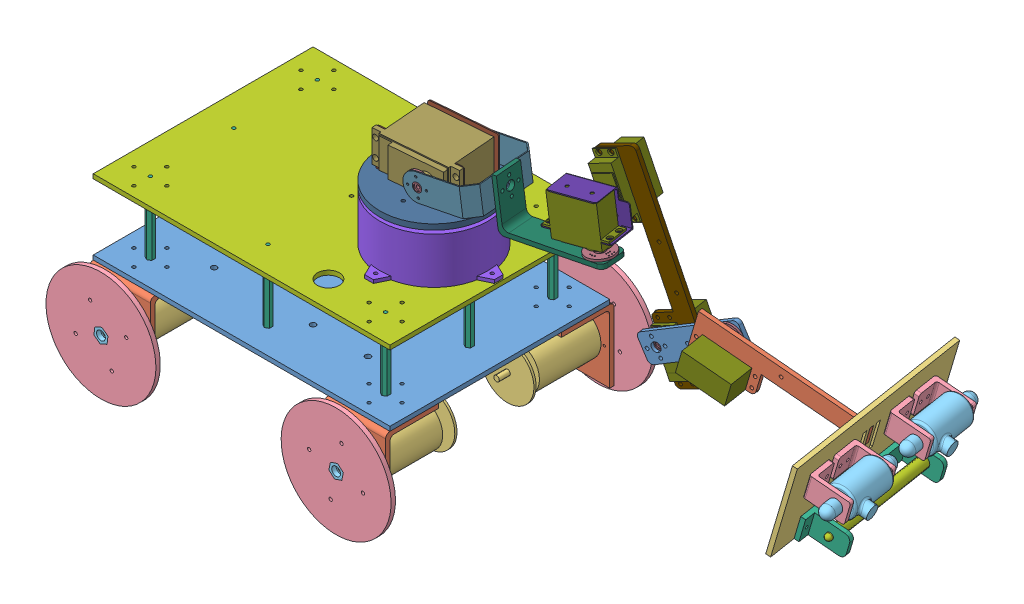
SolidWorks assembly robot, configuration Default. Lengths in mm.
Overall size (661.79 298.94 252.45).
55 component instances, 25 part files, 131 mates.
Components (placement in the parent):
- base_odroid_down_fix-1: base_odroid_down_fix [Default] at (39.4639 122.941 229.7749) x (1 0 0) z (0 -1 0) size (270 200 4)
- link_motor_1_port-1: link_motor_1_port [Default] at (221.3654 112.3394 287.3354) x (0 0 -1) z (1 0 0) size (48 66 56)
- motor_dc_NISCA-1: motor_dc_NISCA [Default] at (244.2642 39.7289 313.6416) x (0 -1 0) z (0 0 -1) size (54 48 92)
- roda_shaft-1: roda_shaft [Default] at (185.8398 121.6563 330.6416) x (-0.980223 0.197896 0) z (0 0 1) size (100 100 4)
- shaft_adapter_5mm-1: shaft_adapter_5mm [Default] at (248.7954 72.9583 317.6416) x (0.980223 -0.197896 0) z (0 0 1) size (12 13.86 17)
- link_motor_1_port-2: link_motor_1_port [Default] at (221.3654 112.3394 139.9479) x (0 0 1) z (-1 0 0) size (48 66 56)
- motor_dc_NISCA-2: motor_dc_NISCA [Default] at (198.4666 39.7289 113.6416) x (0 -1 0) z (0 0 1) size (54 48 92)
- shaft_adapter_5mm-3: shaft_adapter_5mm [Default] at (238.0112 59.5291 109.6416) x (0.404857 -0.91438 0) z (0 0 -1) size (12 13.86 17)
- roda_shaft-2: roda_shaft [Default] at (222.1063 135.748 96.6416) x (0.589448 0.807807 0) z (0 0 -1) size (100 100 4)
- link_motor_1_port-5: link_motor_1_port [Default] at (7.3654 112.3394 287.3354) x (0 0 -1) z (1 0 0) size (48 66 56)
- motor_dc_NISCA-5: motor_dc_NISCA [Default] at (-15.5334 128.1531 313.6416) x (0 1 0) z (0 0 -1) size (54 48 92)
- roda_shaft-5: roda_shaft [Default] at (51.5287 56.8466 334.6416) x (0.393495 -0.919327 0) z (0 0 -1) size (100 100 4)
- shaft_adapter_5mm-6: shaft_adapter_5mm [Default] at (0.8367 112.7577 317.6416) x (-0.393495 0.919327 0) z (0 0 1) size (12 13.86 17)
- link_motor_1_port-6: link_motor_1_port [Default] at (7.3654 112.3394 139.9479) x (0 0 1) z (-1 0 0) size (48 66 56)
- motor_dc_NISCA-6: motor_dc_NISCA [Default] at (-15.5334 39.7289 113.6416) x (0 -1 0) z (0 0 1) size (54 48 92)
- roda_shaft-6: roda_shaft [Default] at (45.258 48.6046 96.6416) x (0.202799 -0.97922 0) z (0 0 -1) size (100 100 4)
- shaft_adapter_5mm-7: shaft_adapter_5mm [Default] at (36.6325 79.8838 109.6416) x (0.949429 -0.313981 0) z (0 0 -1) size (12 13.86 17)
- spacer_6cm-2: spacer_6cm [Default] at (221.7099 182.941 288.7798) x (0.5 0 -0.866025) z (0 -1 0) size (6 6.93 68)
- spacer_6cm-3: spacer_6cm [Default] at (114.7099 182.941 288.7798) x (0.5 0 -0.866025) z (0 -1 0) size (6 6.93 68)
- spacer_6cm-4: spacer_6cm [Default] at (7.7099 182.941 288.7798) x (0.5 0 -0.866025) z (0 -1 0) size (6 6.93 68)
- spacer_6cm-5: spacer_6cm [Default] at (221.7099 182.941 212.7798) x (0.5 0 -0.866025) z (0 -1 0) size (6 6.93 68)
- spacer_6cm-7: spacer_6cm [Default] at (7.7099 182.941 212.7798) x (0.5 0 -0.866025) z (0 -1 0) size (6 6.93 68)
- spacer_6cm-8: spacer_6cm [Default] at (221.7099 182.941 136.7798) x (0.5 0 -0.866025) z (0 -1 0) size (6 6.93 68)
- spacer_6cm-9: spacer_6cm [Default] at (114.7099 182.941 136.7798) x (0.5 0 -0.866025) z (0 -1 0) size (6 6.93 68)
- spacer_6cm-10: spacer_6cm [Default] at (7.7099 182.941 136.7798) x (0.5 0 -0.866025) z (0 -1 0) size (6 6.93 68)
- base_odroid_up_fix-1: base_odroid_up_fix [Default] at (189.2669 186.941 197.5083) x (-1 0 0) z (0 -1 0) size (270 200 4)
- base_arm-1: base_arm [Default] at (189.3654 194.0898 219.4289) x (0 0 1) z (-1 0 0) size (118.01 42 118.01)
- servo_hs422-1: servo_hs422 [Default] at (199.6524 210.6756 203.7356) x (0 0 1) z (-1 0 0) size (19.81 42.14 58.23)
- link1_arm-1: link1_arm [Default] at (162.8005 232.0663 215.7774) x (-0.996784 0 0.080141) z (0 1 0) size (98 98 12)
- bracket_servo_hs755-1: bracket_servo_hs755 [Default] at (229.3889 266.4802 249.7627) x (0.080141 0 0.996784) z (-0.996784 0 0.080141) size (44 34 74)
- servo_hs755-1: servo_hs755 [Default] at (197.4303 211.9363 187.9125) x (0 -1 0) z (0.080141 0 0.996784) size (29 74 56.99)
- servo_horn_general-1: servo_horn_general [Default] at (161.8295 247.7173 249.9552) x (-0.987951 -0.132827 0.07943) z (-0.080141 0 -0.996784) size (24 24 6)
- link2_ubracket-2: link2_ubracket [Default] at (240.8328 274.1378 198.1638) x (-0.080141 0 -0.996784) z (0.1324 -0.991139 -0.010645) size (66 59 24)
- link2_fix-2: link2_fix [Default] at (299.0179 277.8626 194.3678) x (-0.1324 0.991139 0.010645) z (0.080141 0 0.996784) size (45.14 89 24)
- servo_horn_general-2: servo_horn_general [Default] at (284.7702 239.5829 204.3668) x (-0.987951 -0.132827 0.07943) z (-0.1324 0.991139 0.010645) size (24 24 6)
- servo_hs645-2: servo_hs645 [Default] at (369.3996 295.5758 210.2508) x (0.977362 0.132332 -0.165079) z (0.1324 -0.991139 -0.010645) size (53.34 19.56 42.35)
- bracket_servo_645-2: bracket_servo_645 [Default] at (347.8726 246.1813 195.0971) x (0.1324 -0.991139 -0.010645) z (-0.977362 -0.132332 0.165079) size (34 24 57)
- servo_horn_general-3: servo_horn_general [Default] at (277.6371 270.7769 198.3256) x (-0.978327 0.128702 0.162209) z (-0.165025 -0.011453 -0.986223) size (24 24 6)
- servo_hs645-3: servo_hs645 [Default] at (344.7059 232.8318 142.5694) x (0.379271 -0.923782 -0.052736) z (0.165025 0.011453 0.986223) size (53.34 19.56 42.35)
- link4_fix-1: link4_fix [Default] at (380.9777 101.6658 161.2675) x (0.379271 -0.923782 -0.052736) z (0.165025 0.011453 0.986223) size (176.25 35 4)
- servo_hs645-4: servo_hs645 [Default] at (325.2729 210.3912 140.3518) x (-0.379271 0.923782 0.052736) z (0.165025 0.011453 0.986223) size (53.34 19.56 42.35)
- link5_fix-1: link5_fix [Default] at (359.9362 227.0912 179.3318) x (-0.462668 0.883985 0.067153) z (0.165025 0.011453 0.986223) size (24 90 4)
- servo_horn_general-4: servo_horn_general [Default] at (321.7006 151.6934 186.6053) x (-0.871037 -0.467376 0.151178) z (-0.165025 -0.011453 -0.986223) size (24 24 6)
- servo_horn_general-5: servo_horn_general [Default] at (461.1917 226.2323 166.4545) x (0.871037 0.467376 -0.151178) z (0.165025 0.011453 0.986223) size (24 24 6)
- servo_hs645-5: servo_hs645 [Default] at (388.7583 231.4902 223.4879) x (-0.953883 0.25607 0.15664) z (-0.165025 -0.011453 -0.986223) size (53.34 19.56 42.35)
- link6_eff-1: link6_eff [Default] at (386.3105 210.0758 200.9019) x (-0.953883 0.25607 0.15664) z (-0.165025 -0.011453 -0.986223) size (140.63 35 4)
- base_link_effector_fix-2: base_link_effector_fix [Default] at (543.3424 202.5775 175.4232) x (-0.165025 -0.011453 -0.986223) z (0.953883 -0.25607 -0.15664) size (180 80 4)
- base_webcam_fix1-2: base_webcam_fix1 [Default] at (558.36 202.6941 241.1484) x (-0.165025 -0.011453 -0.986223) z (-0.250748 -0.96659 0.053182) size (23 34 20)
- base_webcam_fix1-3: base_webcam_fix1 [Default] at (544.9288 182.7782 191.9147) x (0.165025 0.011453 0.986223) z (0.250748 0.96659 -0.053182) size (23 34 20)
- base_webcam_fix1-4: base_webcam_fix1 [Default] at (543.6728 201.6748 153.3746) x (-0.165025 -0.011453 -0.986223) z (-0.250748 -0.96659 0.053182) size (23 34 20)
- base_webcam_fix1-5: base_webcam_fix1 [Default] at (530.2416 181.7589 104.1409) x (0.165025 0.011453 0.986223) z (0.250748 0.96659 -0.053182) size (23 34 20)
- webcam_sturdy-3: webcam_sturdy [Default] at (570.2782 186.2948 187.3169) x (-0.165025 -0.011453 -0.986223) z (0.953883 -0.25607 -0.15664) size (79 27 33.5)
- webcam_sturdy-4: webcam_sturdy [Default] at (555.5909 185.2756 99.5431) x (-0.165025 -0.011453 -0.986223) z (0.953883 -0.25607 -0.15664) size (79 27 33.5)
- base_GM-1: base_GM [Default] at (537.7124 159.212 133.8436) x (-0.165025 -0.011453 -0.986223) z (-0.250748 -0.96659 0.053182) size (128 34 20)
- tabung_GM-1: tabung_GM [Default] at (565.3856 190.6554 118.4363) x (0.246294 0.967775 -0.052451) z (0.165025 0.011453 0.986223) size (10 10 116)
Mates (geometry in assembly coordinates):
- Coincident1: coincident anti-aligned: plane of link_motor_1_port-1 through (193.3654 52.941 313.6416) normal (0 0 -1); plane of motor_dc_NISCA-1 through (221.3654 83.941 313.6416) normal (0 0 1)
- Concentric1: concentric aligned: cylinder of link_motor_1_port-1 through (221.3654 83.941 317.6416) axis (0 0 -1) radius 9.5; cylinder of motor_dc_NISCA-1 through (221.3654 83.941 317.6416) axis (0 0 -1) radius 9
- Concentric2: concentric anti-aligned: cylinder of link_motor_1_port-1 through (221.3654 106.941 317.6416) axis (0 0 -1) radius 1; cylinder of motor_dc_NISCA-1 through (221.3654 106.941 311.6416) axis (0 0 1) radius 1.5
- Coincident2: coincident anti-aligned: plane of motor_dc_NISCA-1 through (244.2642 39.7289 317.6416) normal (0 0 1); plane of shaft_adapter_5mm-1 through (221.3654 83.941 317.6416) normal (0 0 -1)
- Concentric4: concentric aligned: cylinder of motor_dc_NISCA-1 through (221.3654 83.941 330.6416) axis (0 0 -1) radius 2.5; cylinder of shaft_adapter_5mm-1 through (221.3654 83.941 330.6416) axis (0 0 -1) radius 2.5
- Coincident3: coincident anti-aligned: plane of roda_shaft-1 through (222.7365 90.7322 330.6416) normal (0.318728 -0.947846 0); plane of shaft_adapter_5mm-1 through (222.7365 90.7322 334.6416) normal (-0.318728 0.947846 0)
- Coincident4: coincident aligned: plane of roda_shaft-1 through (221.3654 83.941 334.6416) normal (0 0 1); plane of shaft_adapter_5mm-1 through (248.7954 72.9583 334.6416) normal (0 0 1)
- Coincident7: coincident anti-aligned: plane of roda_shaft-1 through (214.7985 81.7328 330.6416) normal (0.661495 0.74995 0); plane of shaft_adapter_5mm-1 through (214.7985 81.7328 334.6416) normal (-0.661495 -0.74995 0)
- Coincident8: coincident anti-aligned: plane of link_motor_1_port-2 through (249.3654 52.941 113.6416) normal (0 0 1); plane of motor_dc_NISCA-2 through (221.3654 83.941 113.6416) normal (0 0 -1)
- Concentric5: concentric aligned: cylinder of link_motor_1_port-2 through (221.3654 83.941 109.6416) axis (0 0 1) radius 9.5; cylinder of motor_dc_NISCA-2 through (221.3654 83.941 109.6416) axis (0 0 1) radius 9
- Concentric7: concentric anti-aligned: cylinder of link_motor_1_port-2 through (221.3654 106.941 109.6416) axis (0 0 1) radius 1; cylinder of motor_dc_NISCA-2 through (221.3654 106.941 115.6416) axis (0 0 -1) radius 1.5
- Coincident9: coincident anti-aligned: plane of base_odroid_down_fix-1 through (39.4639 118.941 229.7749) normal (0 -1 0); plane of link_motor_1_port-1 through (193.3654 118.941 269.6416) normal (0 1 0)
- Concentric8: concentric anti-aligned: cylinder of base_odroid_down_fix-1 through (206.3654 118.941 289.6416) axis (0 1 0) radius 1.5; cylinder of link_motor_1_port-1 through (206.3654 118.941 289.6416) axis (0 -1 0) radius 1.5
- Concentric9: concentric anti-aligned: cylinder of base_odroid_down_fix-1 through (236.3654 118.941 289.6416) axis (0 1 0) radius 1.5; cylinder of link_motor_1_port-1 through (236.3654 118.941 289.6416) axis (0 -1 0) radius 1.5
- Coincident11: coincident aligned: plane of shaft_adapter_5mm-3 through (238.0112 59.5291 92.6416) normal (0 0 -1); plane of roda_shaft-2 through (221.3654 83.941 92.6416) normal (0 0 -1)
- Coincident12: coincident anti-aligned: plane of shaft_adapter_5mm-3 through (220.627 77.0523 92.6416) normal (-0.589448 -0.807807 0); plane of roda_shaft-2 through (220.627 77.0523 96.6416) normal (0.589448 0.807807 0)
- Coincident13: coincident anti-aligned: plane of shaft_adapter_5mm-3 through (227.7004 86.746 92.6416) normal (0.994305 -0.106573 0); plane of roda_shaft-2 through (227.7004 86.746 96.6416) normal (-0.994305 0.106573 0)
- Coincident14: coincident anti-aligned: plane of motor_dc_NISCA-2 through (198.4666 39.7289 109.6416) normal (0 0 -1); plane of shaft_adapter_5mm-3 through (221.3654 83.941 109.6416) normal (0 0 1)
- Concentric10: concentric aligned: cylinder of motor_dc_NISCA-2 through (221.3654 83.941 96.6416) axis (0 0 1) radius 2.5; cylinder of shaft_adapter_5mm-3 through (221.3654 83.941 96.6416) axis (0 0 1) radius 2.5
- Coincident15: coincident anti-aligned: plane of base_odroid_down_fix-1 through (39.4639 118.941 229.7749) normal (0 -1 0); plane of link_motor_1_port-2 through (249.3654 118.941 157.6416) normal (0 1 0)
- Concentric11: concentric anti-aligned: cylinder of base_odroid_down_fix-1 through (206.3654 118.941 137.6416) axis (0 1 0) radius 1.5; cylinder of link_motor_1_port-2 through (206.3654 118.941 137.6416) axis (0 -1 0) radius 1.5
- Concentric12: concentric anti-aligned: cylinder of base_odroid_down_fix-1 through (236.3654 118.941 137.6416) axis (0 1 0) radius 1.5; cylinder of link_motor_1_port-2 through (236.3654 118.941 137.6416) axis (0 -1 0) radius 1.5
- Coincident16: coincident anti-aligned: plane of link_motor_1_port-5 through (-20.6346 52.941 313.6416) normal (0 0 -1); plane of motor_dc_NISCA-5 through (7.3654 83.941 313.6416) normal (0 0 1)
- Concentric13: concentric aligned: cylinder of link_motor_1_port-5 through (7.3654 83.941 317.6416) axis (0 0 -1) radius 9.5; cylinder of motor_dc_NISCA-5 through (7.3654 83.941 317.6416) axis (0 0 -1) radius 9
- Concentric14: concentric anti-aligned: cylinder of link_motor_1_port-5 through (7.3654 106.941 317.6416) axis (0 0 -1) radius 1; cylinder of motor_dc_NISCA-5 through (7.3654 106.941 311.6416) axis (0 0 1) radius 1.5
- Concentric16: concentric aligned: cylinder of motor_dc_NISCA-5 through (7.3654 83.941 330.6416) axis (0 0 -1) radius 2.5; cylinder of shaft_adapter_5mm-6 through (7.3654 83.941 330.6416) axis (0 0 -1) radius 2.5
- Coincident17: coincident anti-aligned: plane of motor_dc_NISCA-5 through (-15.5334 128.1531 317.6416) normal (0 0 1); plane of shaft_adapter_5mm-6 through (7.3654 83.941 317.6416) normal (0 0 -1)
- Coincident18: coincident anti-aligned: plane of roda_shaft-5 through (6.5417 77.062 334.6416) normal (0.599413 0.80044 0); plane of shaft_adapter_5mm-6 through (0.9961 81.2148 334.6416) normal (-0.599413 -0.80044 0)
- Coincident19: coincident aligned: plane of roda_shaft-5 through (7.3654 83.941 334.6416) normal (0 0 1); plane of shaft_adapter_5mm-6 through (0.8367 112.7577 334.6416) normal (0 0 1)
- Coincident20: coincident anti-aligned: plane of roda_shaft-5 through (1.8198 88.0939 334.6416) normal (0.393495 -0.919327 0); plane of shaft_adapter_5mm-6 through (8.1891 90.8201 334.6416) normal (-0.393495 0.919327 0)
- Coincident21: coincident anti-aligned: plane of base_odroid_down_fix-1 through (39.4639 118.941 229.7749) normal (0 -1 0); plane of link_motor_1_port-5 through (-20.6346 118.941 269.6416) normal (0 1 0)
- Concentric17: concentric anti-aligned: cylinder of base_odroid_down_fix-1 through (-7.6346 118.941 289.6416) axis (0 1 0) radius 1.5; cylinder of link_motor_1_port-5 through (-7.6346 118.941 289.6416) axis (0 -1 0) radius 1.5
- Concentric18: concentric anti-aligned: cylinder of base_odroid_down_fix-1 through (22.3654 118.941 289.6416) axis (0 1 0) radius 1.5; cylinder of link_motor_1_port-5 through (22.3654 118.941 289.6416) axis (0 -1 0) radius 1.5
- Coincident22: coincident anti-aligned: plane of link_motor_1_port-6 through (35.3654 52.941 113.6416) normal (0 0 1); plane of motor_dc_NISCA-6 through (7.3654 83.941 113.6416) normal (0 0 -1)
- Concentric19: concentric aligned: cylinder of link_motor_1_port-6 through (7.3654 83.941 109.6416) axis (0 0 1) radius 9.5; cylinder of motor_dc_NISCA-6 through (7.3654 83.941 109.6416) axis (0 0 1) radius 9
- Concentric20: concentric anti-aligned: cylinder of link_motor_1_port-6 through (7.3654 106.941 109.6416) axis (0 0 1) radius 1; cylinder of motor_dc_NISCA-6 through (7.3654 106.941 115.6416) axis (0 0 -1) radius 1.5
- Concentric21: concentric aligned: cylinder of motor_dc_NISCA-6 through (7.3654 83.941 96.6416) axis (0 0 1) radius 2.5; cylinder of shaft_adapter_5mm-7 through (7.3654 83.941 96.6416) axis (0 0 1) radius 2.5
- Coincident23: coincident anti-aligned: plane of motor_dc_NISCA-6 through (-15.5334 39.7289 109.6416) normal (0 0 -1); plane of shaft_adapter_5mm-7 through (7.3654 83.941 109.6416) normal (0 0 1)
- Coincident24: coincident aligned: plane of roda_shaft-6 through (7.3654 83.941 92.6416) normal (0 0 -1); plane of shaft_adapter_5mm-7 through (36.6325 79.8838 92.6416) normal (0 0 -1)
- Coincident25: coincident anti-aligned: plane of roda_shaft-6 through (2.7565 89.1138 96.6416) normal (0.202799 -0.97922 0); plane of shaft_adapter_5mm-7 through (2.7565 89.1138 92.6416) normal (-0.202799 0.97922 0)
- Coincident26: coincident anti-aligned: plane of roda_shaft-6 through (5.1901 77.3632 96.6416) normal (0.74663 0.665239 0); plane of shaft_adapter_5mm-7 through (5.1901 77.3632 92.6416) normal (-0.74663 -0.665239 0)
- Coincident27: coincident anti-aligned: plane of base_odroid_down_fix-1 through (39.4639 118.941 229.7749) normal (0 -1 0); plane of link_motor_1_port-6 through (35.3654 118.941 157.6416) normal (0 1 0)
- Concentric22: concentric anti-aligned: cylinder of base_odroid_down_fix-1 through (-7.6346 118.941 137.6416) axis (0 1 0) radius 1.5; cylinder of link_motor_1_port-6 through (-7.6346 118.941 137.6416) axis (0 -1 0) radius 1.5
- Concentric23: concentric anti-aligned: cylinder of base_odroid_down_fix-1 through (22.3654 118.941 137.6416) axis (0 1 0) radius 1.5; cylinder of link_motor_1_port-6 through (22.3654 118.941 137.6416) axis (0 -1 0) radius 1.5
- Concentric24: concentric aligned: cylinder of base_odroid_down_fix-1 through (221.3654 118.941 289.6416) axis (0 1 0) radius 1.5; cylinder of spacer_6cm-2 through (221.3654 118.941 289.6416) axis (0 1 0) radius 1.5
- Coincident28: coincident anti-aligned: plane of base_odroid_down_fix-1 through (39.4639 122.941 229.7749) normal (0 1 0); plane of spacer_6cm-2 through (221.7099 122.941 288.7798) normal (0 -1 0)
- Parallel2: parallel aligned: plane of base_odroid_down_fix-1 through (249.3654 118.941 229.7749) normal (1 0 0); plane of spacer_6cm-2 through (224.3654 122.941 287.9096) normal (1 0 0)
- Concentric25: concentric anti-aligned: cylinder of spacer_6cm-2 through (221.3654 186.941 289.6416) axis (0 -1 0) radius 1.5; cylinder of base_odroid_up_fix-1 through (221.3654 182.941 289.6416) axis (0 1 0) radius 1.5
- Concentric26: concentric anti-aligned: cylinder of spacer_6cm-7 through (7.3654 186.941 213.6416) axis (0 -1 0) radius 1.5; cylinder of base_odroid_up_fix-1 through (7.3654 182.941 213.6416) axis (0 1 0) radius 1.5
- Coincident29: coincident anti-aligned: plane of spacer_6cm-2 through (221.7099 182.941 288.7798) normal (0 1 0); plane of base_odroid_up_fix-1 through (189.2669 182.941 197.5083) normal (0 -1 0)
- Coincident31: coincident anti-aligned: plane of base_arm-1 through (189.3654 225.941 213.6416) normal (0 -1 0); plane of servo_hs422-1 through (199.6524 225.941 203.7356) normal (0 1 0)
- Parallel3: parallel aligned: plane of base_odroid_up_fix-1 through (249.3654 182.941 197.5083) normal (1 0 0); plane of servo_hs422-1 through (219.5914 210.6756 223.5476) normal (1 0 0)
- Coincident33: coincident anti-aligned: plane of base_odroid_up_fix-1 through (189.2669 186.941 197.5083) normal (0 1 0); plane of base_arm-1 through (189.3654 186.941 259.6416) normal (0 -1 0)
- Concentric28: concentric anti-aligned: cylinder of base_odroid_up_fix-1 through (242.3654 182.941 213.6416) axis (0 1 0) radius 1.5; cylinder of base_arm-1 through (242.3654 189.941 213.6416) axis (0 -1 0) radius 1.5
- Concentric29: concentric anti-aligned: cylinder of base_odroid_up_fix-1 through (189.3654 182.941 160.6416) axis (0 1 0) radius 1.5; cylinder of base_arm-1 through (189.3654 189.941 160.6416) axis (0 -1 0) radius 1.5
- Parallel5: parallel aligned: plane of base_odroid_up_fix-1 through (189.2669 182.941 113.6416) normal (0 0 -1); plane of servo_hs422-1 through (199.6524 210.6756 203.7356) normal (0 0 -1)
- Concentric30: concentric aligned: cylinder of base_arm-1 through (189.3654 225.941 213.6416) axis (0 1 0) radius 5.4623; cylinder of servo_hs422-1 through (189.3654 202.0734 213.6416) axis (0 1 0) radius 6.4897
- Concentric31: concentric aligned: cylinder of servo_hs422-1 through (189.3654 212.8107 213.6416) axis (0 1 0) radius 2.8131; cylinder of link1_arm-1 through (189.3654 228.0663 213.6416) axis (0 1 0) radius 3
- Coincident36: coincident anti-aligned: plane of servo_hs422-1 through (199.6524 232.0663 223.5476) normal (0 1 0); plane of link1_arm-1 through (189.3654 232.0663 213.6416) normal (0 -1 0)
- Concentric32: concentric aligned: cylinder of link1_arm-1 through (189.3654 240.0663 213.6416) axis (0 -1 0) radius 4; cylinder of bracket_servo_hs755-1 through (189.3654 238.0663 213.6416) axis (0 -1 0) radius 4
- Coincident38: coincident anti-aligned: plane of link1_arm-1 through (189.3654 237.0663 213.6416) normal (0 1 0); plane of bracket_servo_hs755-1 through (150.0802 237.0663 186.7033) normal (0 -1 0)
- Concentric33: concentric anti-aligned: cylinder of link1_arm-1 through (181.3911 232.0663 214.2827) axis (0 1 0) radius 1.5; cylinder of bracket_servo_hs755-1 through (181.3911 238.0663 214.2827) axis (0 -1 0) radius 1.5
- Coincident40: coincident anti-aligned: plane of bracket_servo_hs755-1 through (153.6064 237.0663 230.5618) normal (0.080141 0 0.996784); plane of servo_hs755-1 through (200.5558 211.9363 226.7871) normal (-0.080141 0 -0.996784)
- Concentric36: concentric aligned: cylinder of bracket_servo_hs755-1 through (156.5166 248.5663 229.3246) axis (0.080141 0 0.996784) radius 1.5; cylinder of servo_hs755-1 through (156.5967 248.5663 230.3214) axis (0.080141 0 0.996784) radius 2.5
- Concentric37: concentric aligned: cylinder of bracket_servo_hs755-1 through (224.2979 264.5663 223.875) axis (0.080141 0 0.996784) radius 1.5; cylinder of servo_hs755-1 through (224.378 264.5663 224.8718) axis (0.080141 0 0.996784) radius 2.5
- Concentric39: concentric anti-aligned: cylinder of servo_hs755-1 through (207.3792 257.0663 244.2865) axis (-0.080141 0 -0.996784) radius 3; cylinder of servo_horn_general-1 through (207.1388 257.0663 241.2962) axis (0.080141 0 0.996784) radius 3
- Coincident41: coincident anti-aligned: plane of servo_hs755-1 through (207.3792 257.0663 244.2865) normal (0.080141 0 0.996784); plane of servo_horn_general-1 through (207.3792 257.0663 244.2865) normal (-0.080141 0 -0.996784)
- Concentric40: concentric anti-aligned: cylinder of servo_horn_general-1 through (207.6197 257.0663 247.2769) axis (-0.080141 0 -0.996784) radius 4; cylinder of link2_ubracket-2 through (207.5395 257.0663 246.2801) axis (0.080141 0 0.996784) radius 4
- Coincident42: coincident anti-aligned: plane of servo_horn_general-1 through (207.5395 257.0663 246.2801) normal (0.080141 0 0.996784); plane of link2_ubracket-2 through (245.852 250.11 243.1998) normal (-0.080141 0 -0.996784)
- Concentric41: concentric aligned: cylinder of servo_horn_general-1 through (206.32 264.9954 244.3717) axis (0.080141 0 0.996784) radius 0.5; cylinder of link2_ubracket-2 through (206.4803 264.9954 246.3653) axis (0.080141 0 0.996784) radius 1
- Coincident46: coincident anti-aligned: plane of link2_ubracket-2 through (254.8877 251.4155 234.032) normal (0.987951 0.132827 -0.07943); plane of link2_fix-2 through (251.2849 271.1865 222.2829) normal (-0.987951 -0.132827 0.07943)
- Concentric45: concentric anti-aligned: cylinder of link2_ubracket-2 through (250.3876 263.1763 210.3164) axis (0.987951 0.132827 -0.07943) radius 4; cylinder of link2_fix-2 through (255.3273 263.8405 209.9192) axis (-0.987951 -0.132827 0.07943) radius 4
- Concentric46: concentric anti-aligned: cylinder of link2_ubracket-2 through (249.7465 263.1763 202.3421) axis (0.987951 0.132827 -0.07943) radius 1; cylinder of link2_fix-2 through (254.6862 263.8405 201.9449) axis (-0.987951 -0.132827 0.07943) radius 1.5
- Coincident47: coincident anti-aligned: plane of servo_horn_general-2 through (330.8902 247.7672 203.844) normal (-0.1324 0.991139 0.010645); plane of servo_hs645-2 through (330.8902 247.7672 203.844) normal (0.1324 -0.991139 -0.010645)
- Concentric48: concentric anti-aligned: cylinder of servo_horn_general-2 through (330.493 250.7406 203.8759) axis (0.1324 -0.991139 -0.010645) radius 3; cylinder of servo_hs645-2 through (330.8902 247.7672 203.844) axis (-0.1324 0.991139 0.010645) radius 2.9972
- Coincident48: coincident anti-aligned: plane of link2_fix-2 through (305.7008 242.2334 217.9079) normal (-0.1324 0.991139 0.010645); plane of servo_horn_general-2 through (331.155 245.785 203.8227) normal (0.1324 -0.991139 -0.010645)
- Concentric49: concentric anti-aligned: cylinder of link2_fix-2 through (331.155 245.785 203.8227) axis (0.1324 -0.991139 -0.010645) radius 4; cylinder of servo_horn_general-2 through (331.2874 244.7938 203.8121) axis (-0.1324 0.991139 0.010645) radius 4
- Concentric50: concentric aligned: cylinder of link2_fix-2 through (330.5138 245.785 195.8485) axis (0.1324 -0.991139 -0.010645) radius 1.5; cylinder of servo_horn_general-2 through (330.249 247.7672 195.8697) axis (0.1324 -0.991139 -0.010645) radius 0.5
- Coincident50: coincident anti-aligned: plane of servo_hs645-2 through (373.1829 267.254 209.9466) normal (0.1324 -0.991139 -0.010645); plane of bracket_servo_645-2 through (288.6446 256.0929 197.6682) normal (-0.1324 0.991139 0.010645)
- Concentric51: concentric aligned: cylinder of servo_hs645-2 through (342.6829 266.414 207.0627) axis (0.1324 -0.991139 -0.010645) radius 2.5019; cylinder of bracket_servo_645-2 through (342.8994 264.7935 207.0453) axis (0.1324 -0.991139 -0.010645) radius 1.5
- Concentric52: concentric aligned: cylinder of servo_hs645-2 through (295.5154 260.0277 215.0294) axis (0.1324 -0.991139 -0.010645) radius 2.5019; cylinder of bracket_servo_645-2 through (295.7319 258.4072 215.012) axis (0.1324 -0.991139 -0.010645) radius 1.5
- Concentric53: concentric aligned: cylinder of bracket_servo_645-2 through (323.8802 267.9272 191.6347) axis (-0.165025 -0.011453 -0.986223) radius 4; cylinder of servo_horn_general-3 through (323.8802 267.9272 191.6347) axis (-0.165025 -0.011453 -0.986223) radius 4
- Coincident51: coincident anti-aligned: plane of bracket_servo_645-2 through (284.6399 284.8245 196.9906) normal (-0.165025 -0.011453 -0.986223); plane of servo_horn_general-3 through (323.7151 267.9158 190.6485) normal (0.165025 0.011453 0.986223)
- Concentric54: concentric anti-aligned: cylinder of bracket_servo_645-2 through (322.821 275.8563 191.7199) axis (-0.165025 -0.011453 -0.986223) radius 1.5; cylinder of servo_horn_general-3 through (322.3259 275.822 188.7612) axis (0.165025 0.011453 0.986223) radius 0.5
- Coincident52: coincident anti-aligned: plane of servo_horn_general-3 through (323.3851 267.8928 188.6761) normal (-0.165025 -0.011453 -0.986223); plane of servo_hs645-3 through (323.3851 267.8928 188.6761) normal (0.165025 0.011453 0.986223)
- Concentric55: concentric anti-aligned: cylinder of servo_horn_general-3 through (322.89 267.8585 185.7174) axis (0.165025 0.011453 0.986223) radius 3; cylinder of servo_hs645-3 through (323.3851 267.8928 188.6761) axis (-0.165025 -0.011453 -0.986223) radius 2.9972
- Coincident53: coincident anti-aligned: plane of servo_hs645-3 through (349.1491 233.1401 169.1225) normal (-0.165025 -0.011453 -0.986223); plane of link4_fix-1 through (381.6378 101.7116 165.2124) normal (0.165025 0.011453 0.986223)
- Concentric56: concentric aligned: cylinder of servo_hs645-3 through (302.9955 297.9973 174.5469) axis (0.165025 0.011453 0.986223) radius 2.5019; cylinder of link4_fix-1 through (302.5869 297.9689 172.1051) axis (0.165025 0.011453 0.986223) radius 1.5
- Concentric57: concentric aligned: cylinder of servo_hs645-3 through (321.2991 253.4156 172.0019) axis (0.165025 0.011453 0.986223) radius 2.5019; cylinder of link4_fix-1 through (320.8905 253.3872 169.56) axis (0.165025 0.011453 0.986223) radius 1.5
- Coincident54: coincident anti-aligned: plane of link4_fix-1 through (380.9777 101.6658 161.2675) normal (-0.165025 -0.011453 -0.986223); plane of servo_hs645-4 through (329.9885 210.7185 168.5331) normal (0.165025 0.011453 0.986223)
- Concentric58: concentric aligned: cylinder of link4_fix-1 through (357.587 190.4256 164.1507) axis (0.165025 0.011453 0.986223) radius 1.5; cylinder of servo_hs645-4 through (357.063 190.3892 161.0195) axis (0.165025 0.011453 0.986223) radius 2.5019
- Concentric59: concentric aligned: cylinder of link4_fix-1 through (366.6404 141.9552 163.1987) axis (0.165025 0.011453 0.986223) radius 1.5; cylinder of servo_hs645-4 through (366.1165 141.9188 160.0674) axis (0.165025 0.011453 0.986223) radius 2.5019
- Concentric61: concentric anti-aligned: cylinder of servo_hs645-4 through (360.5729 176.3003 177.7871) axis (-0.165025 -0.011453 -0.986223) radius 2.9972; cylinder of servo_horn_general-4 through (360.0778 176.2659 174.8284) axis (0.165025 0.011453 0.986223) radius 3
- Coincident56: coincident anti-aligned: plane of servo_hs645-4 through (360.5729 176.3003 177.7871) normal (0.165025 0.011453 0.986223); plane of servo_horn_general-4 through (360.5729 176.3003 177.7871) normal (-0.165025 -0.011453 -0.986223)
- Coincident57: coincident anti-aligned: plane of link5_fix-1 through (359.9362 227.0912 179.3318) normal (-0.165025 -0.011453 -0.986223); plane of servo_horn_general-4 through (360.9029 176.3232 179.7596) normal (0.165025 0.011453 0.986223)
- Concentric62: concentric anti-aligned: cylinder of link5_fix-1 through (360.9029 176.3232 179.7596) axis (0.165025 0.011453 0.986223) radius 4; cylinder of servo_horn_general-4 through (361.068 176.3347 180.7458) axis (-0.165025 -0.011453 -0.986223) radius 4
- Concentric63: concentric aligned: cylinder of link5_fix-1 through (357.2016 183.3951 180.2968) axis (0.165025 0.011453 0.986223) radius 1.5; cylinder of servo_horn_general-4 through (356.8715 183.3722 178.3243) axis (0.165025 0.011453 0.986223) radius 0.5
- Concentric64: concentric anti-aligned: cylinder of servo_horn_general-5 through (419.8766 207.2731 178.6578) axis (-0.165025 -0.011453 -0.986223) radius 3; cylinder of servo_hs645-5 through (419.3815 207.2387 175.6991) axis (0.165025 0.011453 0.986223) radius 2.9972
- Coincident58: coincident anti-aligned: plane of servo_horn_general-5 through (419.3815 207.2387 175.6991) normal (0.165025 0.011453 0.986223); plane of servo_hs645-5 through (419.3815 207.2387 175.6991) normal (-0.165025 -0.011453 -0.986223)
- Coincident59: coincident anti-aligned: plane of link5_fix-1 through (360.5963 227.137 183.2767) normal (0.165025 0.011453 0.986223); plane of servo_horn_general-5 through (419.0514 207.2158 173.7267) normal (-0.165025 -0.011453 -0.986223)
- Concentric65: concentric aligned: cylinder of link5_fix-1 through (418.3913 207.17 169.7818) axis (0.165025 0.011453 0.986223) radius 4; cylinder of servo_horn_general-5 through (418.8864 207.2044 172.7405) axis (0.165025 0.011453 0.986223) radius 4
- Concentric66: concentric anti-aligned: cylinder of link5_fix-1 through (422.0927 200.0981 169.2446) axis (0.165025 0.011453 0.986223) radius 1.5; cylinder of servo_horn_general-5 through (423.0828 200.1668 175.1619) axis (-0.165025 -0.011453 -0.986223) radius 0.5
- Coincident60: coincident anti-aligned: plane of servo_hs645-5 through (384.3152 231.1819 196.9348) normal (0.165025 0.011453 0.986223); plane of link6_eff-1 through (385.6504 210.03 196.957) normal (-0.165025 -0.011453 -0.986223)
- Concentric67: concentric aligned: cylinder of servo_hs645-5 through (408.1281 206.2153 194.7854) axis (-0.165025 -0.011453 -0.986223) radius 2.5019; cylinder of link6_eff-1 through (408.5367 206.2437 197.2273) axis (-0.165025 -0.011453 -0.986223) radius 1.5
- Concentric68: concentric aligned: cylinder of servo_hs645-5 through (454.1625 193.8574 187.2259) axis (-0.165025 -0.011453 -0.986223) radius 2.5019; cylinder of link6_eff-1 through (454.5711 193.8858 189.6678) axis (-0.165025 -0.011453 -0.986223) radius 1.5
- Coincident61: coincident aligned: plane of link6_eff-1 through (537.9865 169.1354 171.9414) normal (0.953883 -0.25607 -0.15664); plane of base_link_effector_fix-2 through (547.158 201.5532 174.7966) normal (0.953883 -0.25607 -0.15664)
- Coincident62: coincident anti-aligned: plane of link6_eff-1 through (385.6504 210.03 196.957) normal (-0.165025 -0.011453 -0.986223); plane of base_link_effector_fix-2 through (542.2866 201.4439 170.8467) normal (0.165025 0.011453 0.986223)
- Coincident63: coincident anti-aligned: plane of link6_eff-1 through (393.766 241.3142 195.2357) normal (0.250748 0.96659 -0.053182); plane of base_link_effector_fix-2 through (542.9467 201.4897 174.7916) normal (-0.250748 -0.96659 0.053182)
- Coincident72: coincident anti-aligned: plane of base_link_effector_fix-2 through (547.158 201.5532 174.7966) normal (0.953883 -0.25607 -0.15664); plane of base_webcam_fix1-2 through (553.3451 183.3623 242.2121) normal (-0.953883 0.25607 0.15664)
- Concentric71: concentric anti-aligned: cylinder of base_link_effector_fix-2 through (552.8821 192.822 223.9282) axis (-0.953883 0.25607 0.15664) radius 1.5; cylinder of base_webcam_fix1-2 through (552.8821 192.822 223.9282) axis (0.953883 -0.25607 -0.15664) radius 1.5
- Concentric72: concentric anti-aligned: cylinder of base_link_effector_fix-2 through (554.2023 192.9136 231.818) axis (-0.953883 0.25607 0.15664) radius 1.5; cylinder of base_webcam_fix1-2 through (554.2023 192.9136 231.818) axis (0.953883 -0.25607 -0.15664) radius 1.5
- Coincident73: coincident anti-aligned: plane of base_link_effector_fix-2 through (547.158 201.5532 174.7966) normal (0.953883 -0.25607 -0.15664); plane of base_webcam_fix1-3 through (549.9438 202.11 190.8511) normal (-0.953883 0.25607 0.15664)
- Concentric73: concentric anti-aligned: cylinder of base_link_effector_fix-2 through (549.0865 192.5586 201.2451) axis (-0.953883 0.25607 0.15664) radius 1.5; cylinder of base_webcam_fix1-3 through (549.0865 192.5586 201.2451) axis (0.953883 -0.25607 -0.15664) radius 1.5
- Concentric74: concentric anti-aligned: cylinder of base_link_effector_fix-2 through (550.4067 192.6502 209.1349) axis (-0.953883 0.25607 0.15664) radius 1.5; cylinder of base_webcam_fix1-3 through (550.4067 192.6502 209.1349) axis (0.953883 -0.25607 -0.15664) radius 1.5
- Coincident74: coincident anti-aligned: plane of base_link_effector_fix-2 through (547.158 201.5532 174.7966) normal (0.953883 -0.25607 -0.15664); plane of base_webcam_fix1-4 through (538.6578 182.343 154.4382) normal (-0.953883 0.25607 0.15664)
- Concentric75: concentric anti-aligned: cylinder of base_link_effector_fix-2 through (538.1949 191.8027 136.1544) axis (-0.953883 0.25607 0.15664) radius 1.5; cylinder of base_webcam_fix1-4 through (538.1949 191.8027 136.1544) axis (0.953883 -0.25607 -0.15664) radius 1.5
- Concentric76: concentric anti-aligned: cylinder of base_link_effector_fix-2 through (539.5151 191.8944 144.0442) axis (-0.953883 0.25607 0.15664) radius 1.5; cylinder of base_webcam_fix1-4 through (539.5151 191.8944 144.0442) axis (0.953883 -0.25607 -0.15664) radius 1.5
- Coincident75: coincident anti-aligned: plane of base_link_effector_fix-2 through (547.158 201.5532 174.7966) normal (0.953883 -0.25607 -0.15664); plane of base_webcam_fix1-5 through (535.2565 201.0907 103.0772) normal (-0.953883 0.25607 0.15664)
- Concentric77: concentric anti-aligned: cylinder of base_link_effector_fix-2 through (535.7195 191.6309 121.3611) axis (-0.953883 0.25607 0.15664) radius 1.5; cylinder of base_webcam_fix1-5 through (535.7195 191.6309 121.3611) axis (0.953883 -0.25607 -0.15664) radius 1.5
- Concentric78: concentric anti-aligned: cylinder of base_link_effector_fix-2 through (534.3993 191.5393 113.4713) axis (-0.953883 0.25607 0.15664) radius 1.5; cylinder of base_webcam_fix1-5 through (534.3993 191.5393 113.4713) axis (0.953883 -0.25607 -0.15664) radius 1.5
- Concentric79: concentric anti-aligned: cylinder of base_webcam_fix1-2 through (578.0856 186.8367 233.976) axis (0.165025 0.011453 0.986223) radius 6; cylinder of webcam_sturdy-3 through (581.0561 187.0428 251.728) axis (-0.165025 -0.011453 -0.986223) radius 6
- Coincident78: coincident anti-aligned: plane of base_webcam_fix1-3 through (554.4194 201.1315 194.1694) normal (0.165025 0.011453 0.986223); plane of webcam_sturdy-3 through (570.9896 186.3442 191.5684) normal (-0.165025 -0.011453 -0.986223)
- Parallel8: parallel aligned: plane of base_link_effector_fix-2 through (547.158 201.5532 174.7966) normal (0.953883 -0.25607 -0.15664); plane of webcam_sturdy-3 through (595.5131 181.6008 220.981) normal (0.953883 -0.25607 -0.15664)
- Concentric80: concentric anti-aligned: cylinder of base_webcam_fix1-4 through (563.3984 185.8174 146.2022) axis (0.165025 0.011453 0.986223) radius 6; cylinder of webcam_sturdy-4 through (566.3689 186.0235 163.9542) axis (-0.165025 -0.011453 -0.986223) radius 6
- Coincident80: coincident anti-aligned: plane of base_webcam_fix1-5 through (539.7322 200.1122 106.3956) normal (0.165025 0.011453 0.986223); plane of webcam_sturdy-4 through (556.3023 185.3249 103.7946) normal (-0.165025 -0.011453 -0.986223)
- Parallel9: parallel aligned: plane of base_link_effector_fix-2 through (547.158 201.5532 174.7966) normal (0.953883 -0.25607 -0.15664); plane of webcam_sturdy-4 through (580.8258 180.5815 133.2071) normal (0.953883 -0.25607 -0.15664)
- Coincident82: coincident anti-aligned: plane of base_link_effector_fix-2 through (547.158 201.5532 174.7966) normal (0.953883 -0.25607 -0.15664); plane of base_GM-1 through (540.2986 143.0655 228.6396) normal (-0.953883 0.25607 0.15664)
- Concentric81: concentric anti-aligned: cylinder of base_link_effector_fix-2 through (524.1583 151.4373 116.6646) axis (-0.953883 0.25607 0.15664) radius 1.5; cylinder of base_GM-1 through (524.1583 151.4373 116.6646) axis (0.953883 -0.25607 -0.15664) radius 1.5
- Concentric82: concentric anti-aligned: cylinder of base_link_effector_fix-2 through (543.6313 152.7887 233.0389) axis (-0.953883 0.25607 0.15664) radius 1.5; cylinder of base_GM-1 through (543.6313 152.7887 233.0389) axis (0.953883 -0.25607 -0.15664) radius 1.5
- Concentric83: concentric anti-aligned: cylinder of base_GM-1 through (543.7673 146.675 122.5644) axis (-0.165025 -0.011453 -0.986223) radius 3; cylinder of tabung_GM-1 through (542.4471 146.5834 114.6746) axis (0.165025 0.011453 0.986223) radius 3
- Coincident83: coincident anti-aligned: plane of base_GM-1 through (572.0706 134.3133 219.3689) normal (-0.165025 -0.011453 -0.986223); plane of tabung_GM-1 through (560.2698 147.8203 221.1867) normal (0.165025 0.011453 0.986223)
